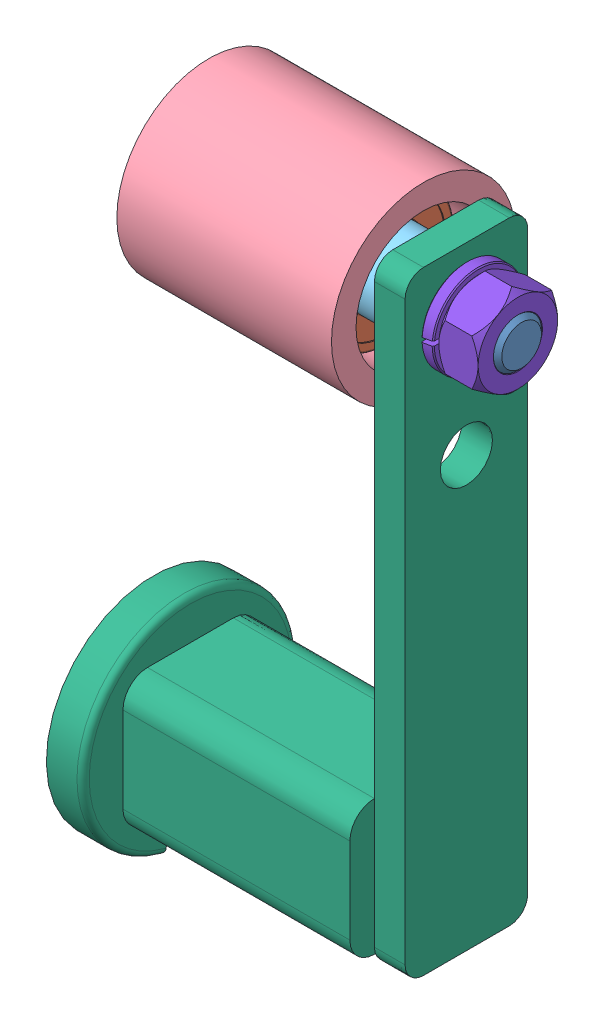
SolidWorks assembly 14087200montiert, configuration Default. Lengths in mm.
Overall size (65.1 112.15 35).
9 component instances, 8 part files, 0 mates.
Components (placement in the parent):
- _schr_sp-rolle_14087200-1: _schr_sp-rolle_14087200 [Default] at origin size (50.3 16.51 13)
- _kglg_sp-rolle_14087200-1: _kglg_sp-rolle_14087200 [Default] at (5.3 0 0) size (7.01 22 22)
- _bu1_sp-rolle_14087200-1: _bu1_sp-rolle_14087200 [Default] at (12.3 0 0) size (9 12.5 12.5)
- _kglg_sp-rolle_14087200-2: _kglg_sp-rolle_14087200 [Default] at (21.3 0 0) size (7.01 22 22)
- _sp-rolle_kst_14087200-1: _sp-rolle_kst_14087200 [Default] at (-0.7 0 0) size (35 30 30)
- _bu2_sp-rolle_14087200-1: _bu2_sp-rolle_14087200 [Default] at (28.3 0 0) size (8 12.5 12.5)
- _spe_sp-rolle_14087200-1: _spe_sp-rolle_14087200 [Default] at (-9.7 -80 0) size (51 107.15 35)
- _schr_spe_sp-rolle_14087200-1: _schr_spe_sp-rolle_14087200 [Default] at (-14.8 -80 0) size (24 12.7 11.8)
- _mu_sp-rolle_14087200-1: _mu_sp-rolle_14087200 [Default] at (41.3 0 0) size (8.4 16.51 14.8)
